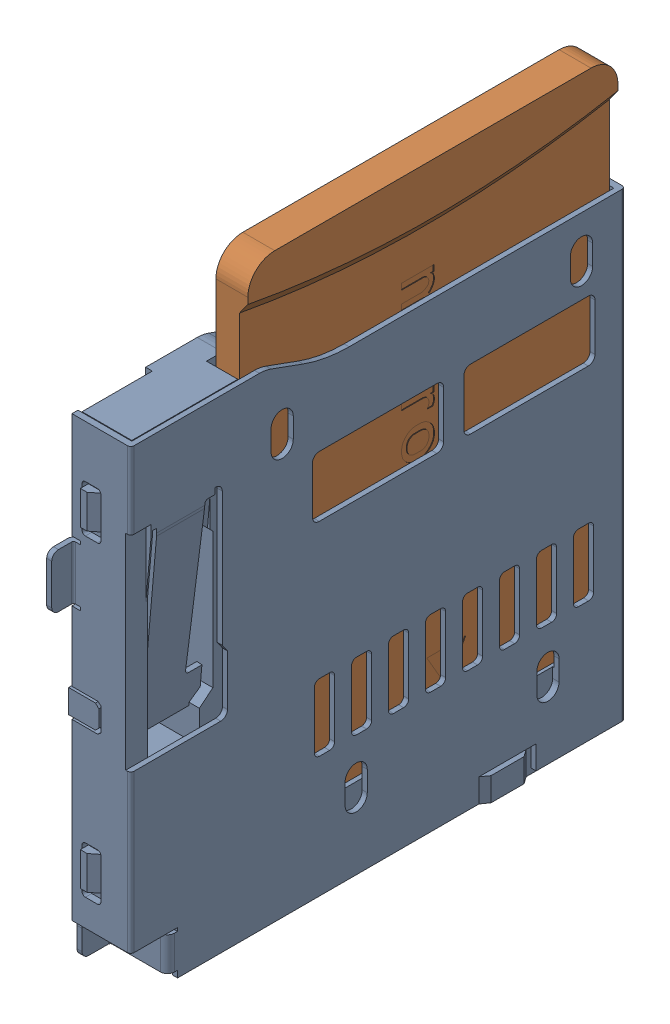
SolidWorks assembly SD card Assem, configuration Default. Lengths in mm.
Overall size (2.44 17.9 16).
2 component instances, 2 part files, 0 mates.
Components (placement in the parent):
- CD card slot-1: CD card slot [Default] at (-120.5536 47.0914 197.6703) x (0 0 1) z (1 0 0) size (16 15 2.44)
- Micro sd card-1: Micro sd card [Default] at (-120.5536 45.5089 151.9853) x (0 0 1) z (1 0 0) size (11 15 0.95)
